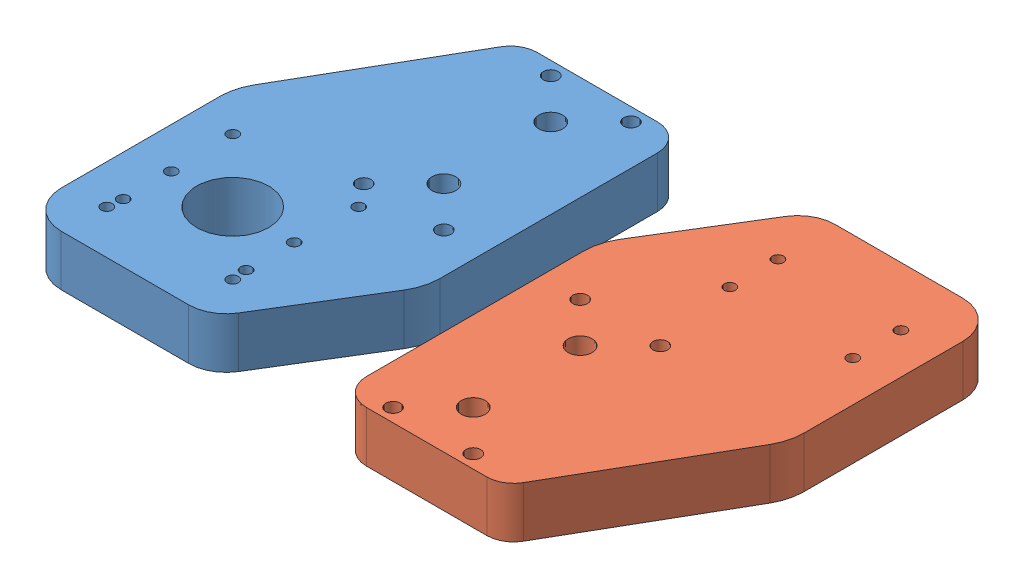
SolidWorks assembly Assem2, configuration Default. Lengths in mm.
Overall size (218.4 19 147).
2 component instances, 2 part files, 6 mates.
Components (placement in the parent):
- Y Screw Support motor top b-2: Y Screw Support motor top b [Default] at (135.0829 0 -470) x (1 0 0) z (0 -1 0) size (100.2 147 19)
- Y Screw Support motor top end-2: Y Screw Support motor top end [Default] at (-6.9171 0 617) x (-1 0 0) z (0 -1 0) size (100.2 147 19)
Mates (geometry in assembly coordinates):
- Coincident1: coincident: point of Y Screw Support motor top b-2; point of assembly
- Parallel1: parallel: plane of Y Screw Support motor top b-2 through (42.0829 -19 3) normal (0 -1 0); plane of assembly
- Coincident3: coincident anti-aligned: plane of Y Screw Support motor top b-2 through (5.7735 -19 0) normal (0 0 -1); plane of assembly
- Coincident4: coincident: plane of Y Screw Support motor top b-2 through (42.0829 -19 3) normal (0 -1 0); plane of Y Screw Support motor top end-2 through (94.0769 -19 144) normal (0 -1 0)
- Coincident5: coincident: plane of Y Screw Support motor top b-2 through (135.0829 177.9018 147) normal (0 0 1); plane of Y Screw Support motor top end-2 through (122.3923 -19 147) normal (0 0 1)
- Distance2: distance = 18 mm anti-aligned: plane of Y Screw Support motor top end-2 through (73.0829 177.9018 617) normal (-1 0 0); plane of Y Screw Support motor top b-2 through (55.0829 177.9018 -470) normal (1 0 0)
